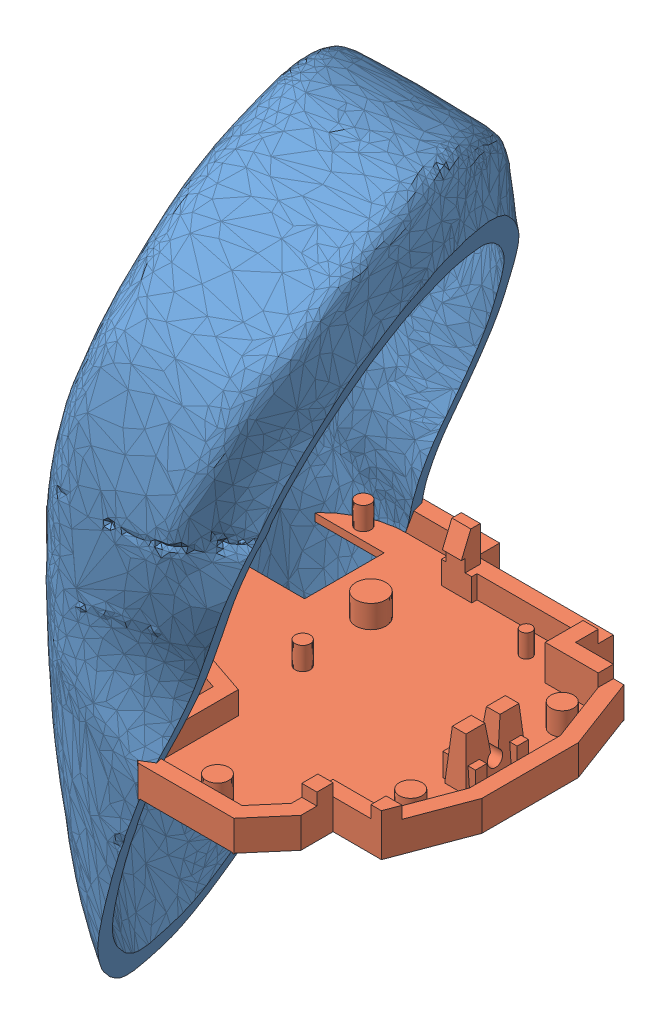
SolidWorks assembly Assem1, configuration Default. Lengths in mm.
Overall size (60.5 123.92 51.81).
2 component instances, 2 part files, 0 mates.
Components (placement in the parent):
- device-1: device [Default] at (1.3085 4.94 2.3451) size (44.47 123.92 51.81)
- housing-1: housing [Default] at (-21.75 0.0382 -22.5) size (60.5 9.38 49)
